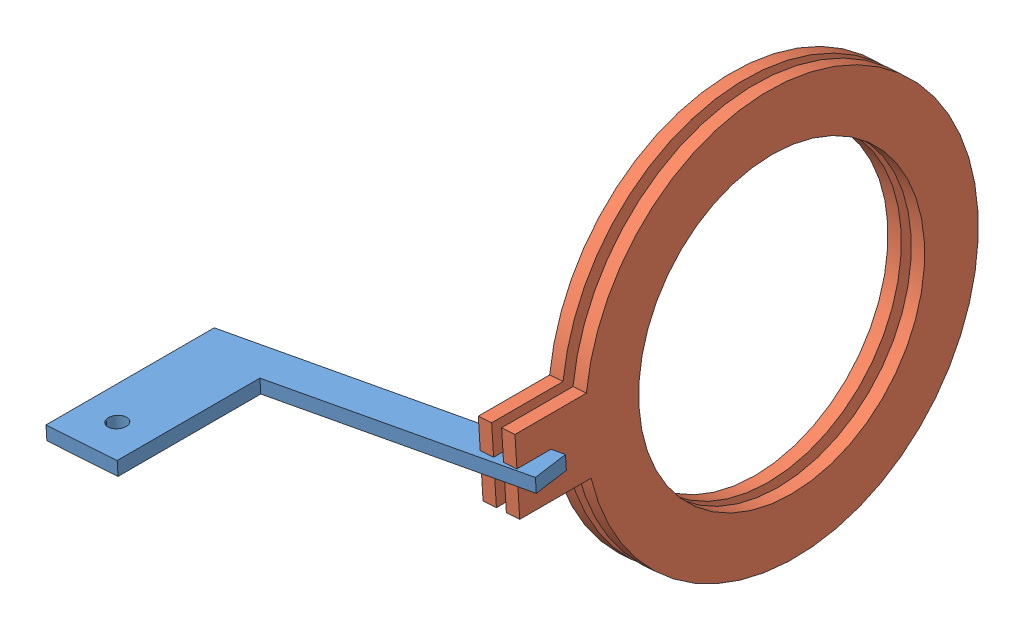
SolidWorks assembly CubeCatchASSEMBLY, configuration Default. Lengths in mm.
Overall size (111.04 140.26 227.18).
3 component instances, 2 part files, 19 mates.
Components (placement in the parent):
- CubeCatchConnector-1: CubeCatchConnector [Default] at (67.755 67.24 88.7789) x (0 0 1) z (0.066757 -0.997769 0) size (76.06 110.97 4.76)
- PopperLocker-1: PopperLocker [Default] at (48.5264 63.5669 -5.0544) x (0.066757 -0.997769 0) z (0 0 1) size (139.7 4.76 163.94)
- PopperLocker-2: PopperLocker [Default] at (56.8263 64.1222 -5.0544) x (0.066757 -0.997769 0) z (0 0 1) size (139.7 4.76 163.94)
Mates (geometry in assembly coordinates):
- Parallel3: parallel anti-aligned: plane of PopperLocker-1 through (53.4372 61.5089 -5.0544) normal (-0.066757 0.997769 0); plane of CubeCatchConnector-3 through (51.0613 61.3499 110.5927) normal (0.066757 -0.997769 0)
- Parallel1: parallel anti-aligned: plane of PopperLocker-1 through (52.7272 72.1214 -5.0544) normal (0.066757 -0.997769 0); plane of CubeCatchConnector-3 through (50.2452 73.5464 104.2427) normal (-0.066757 0.997769 0)
- Parallel2: parallel anti-aligned: plane of PopperLocker-1 through (48.5264 63.5669 -5.0544) normal (-0.997769 -0.066757 0); plane of CubeCatchConnector-3 through (49.1092 54.8551 110.5927) normal (0.997769 0.066757 0)
- Coincident7: coincident anti-aligned: line of PopperLocker-1 through (53.4372 61.5089 84.4669) axis (0 0 1); line of CubeCatchConnector-3 through (53.4372 61.5089 110.5927) axis (0 0 -1)
- Coincident8: coincident aligned: line of PopperLocker-1 through (52.9391 68.9535 110.5927) axis (-0.997769 -0.066757 0); line of CubeCatchConnector-3 through (52.9391 68.9535 110.5927) axis (-0.997769 -0.066757 0)
- Coincident11: coincident anti-aligned: line of CubeCatchConnector-3 through (22.5271 66.9187 136.6277) axis (-0.066757 0.997769 0); line of CubeCatchExtender-1 through (22.3151 70.0866 136.6277) axis (0.066757 -0.997769 0)
- Coincident12: coincident anti-aligned: line of CubeCatchConnector-3 through (17.7752 66.6008 136.6277) axis (-0.066757 0.997769 0); line of CubeCatchExtender-1 through (17.5633 69.7687 136.6277) axis (0.066757 -0.997769 0)
- Coincident13: coincident anti-aligned: plane of CubeCatchConnector-3 through (51.4852 55.0141 110.5927) normal (0 0 1); plane of CubeCatchExtender-1 through (17.7752 66.6008 133.4527) normal (-0.066757 0.997769 0)
- Coincident15: coincident anti-aligned: line of CubeCatchExtender-1 through (17.5633 69.7687 187.4277) axis (0.066757 -0.997769 0); line of CubeCatchMotorConnector-1 through (17.8812 65.0168 187.4277) axis (-0.066757 0.997769 0)
- Coincident16: coincident aligned: line of CubeCatchExtender-1 through (18.6654 53.2955 187.4277) axis (-0.066757 0.997769 0); line of CubeCatchMotorConnector-2 through (18.6654 53.2955 187.4277) axis (-0.066757 0.997769 0)
- Coincident17: coincident anti-aligned: plane of CubeCatchExtender-1 through (18.6654 53.2955 133.4527) normal (-0.066757 0.997769 0); plane of CubeCatchMotorConnector-2 through (26.5852 53.8254 184.2527) normal (0.066757 -0.997769 0)
- Coincident18: coincident anti-aligned: plane of CubeCatchExtender-1 through (17.5633 69.7687 133.4527) normal (0.066757 -0.997769 0); plane of CubeCatchMotorConnector-1 through (25.4831 70.2986 184.2527) normal (-0.066757 0.997769 0)
- Parallel4: parallel aligned: plane of CubeCatchExtender-1 through (19.1741 45.6925 133.4527) normal (-0.997769 -0.066757 0); plane of CubeCatchMotorConnector-2 through (13.9136 52.9776 184.2527) normal (-0.997769 -0.066757 0)
- Parallel5: parallel aligned: plane of CubeCatchExtender-1 through (19.1741 45.6925 133.4527) normal (-0.997769 -0.066757 0); plane of CubeCatchMotorConnector-1 through (13.1293 64.6989 184.2527) normal (-0.997769 -0.066757 0)
- Coincident19: coincident aligned: line of CubeCatchConnector-1 through (53.4372 61.5089 84.4669) axis (-0.997769 -0.066757 0); line of PopperLocker-1 through (53.4372 61.5089 84.4669) axis (-0.997769 -0.066757 0)
- Coincident21: coincident aligned: line of CubeCatchConnector-1 through (53.4372 61.5089 84.4669) axis (-0.997769 -0.066757 0); line of PopperLocker-1 through (53.4372 61.5089 84.4669) axis (-0.997769 -0.066757 0)
- Coincident22: coincident: point of CubeCatchConnector-1; moEndPointRef_w of PopperLocker-1
- Coincident23: coincident: line of CubeCatchConnector-1 through (61.7371 62.0642 84.4669) axis (-0.997769 -0.066757 0); line of PopperLocker-2 through (78.0832 63.1578 84.4669) axis (-0.997769 -0.066757 0)
- Coincident28: coincident anti-aligned: line of CubeCatchConnector-1 through (56.9853 61.7462 84.4669) axis (-0.066757 0.997769 0); line of PopperLocker-2 through (56.6673 66.4981 84.4669) axis (0.066757 -0.997769 0)
